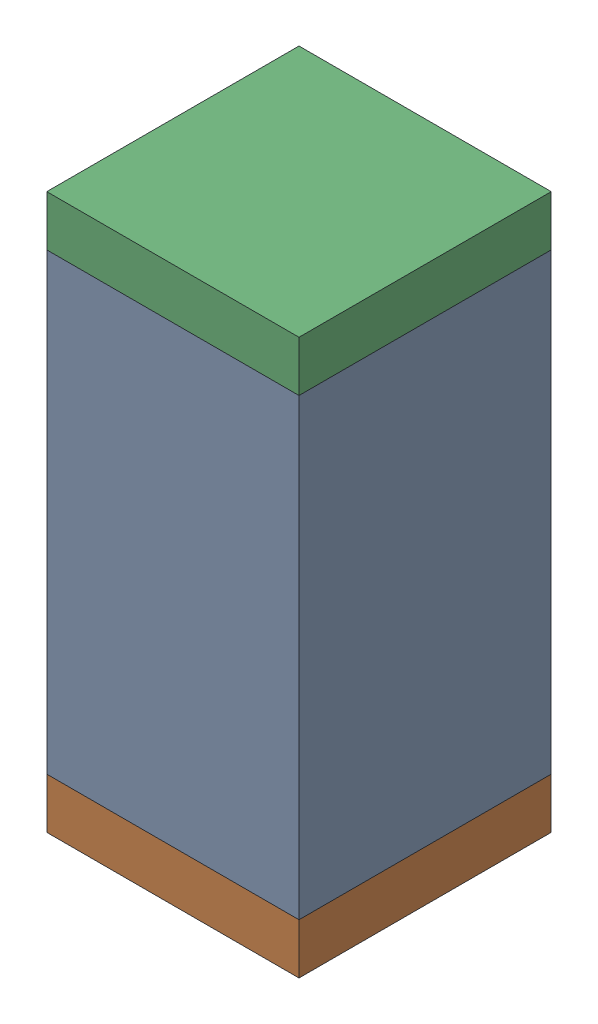
SolidWorks assembly C90, configuration Default. Lengths in mm.
Overall size (0.5 1.1 0.5).
6 component instances, 2 part files, 0 mates.
Components (placement in the parent):
- 791586336-1: 791586336 [Default] at (110.3 65.85 0) size (0.5 0.9 0.5)
  - Extruded_8-1: Extruded_8 [Default] at origin size (0.5 0.9 0.5)
- 810157360-1: 810157360 [Default] at (110.3 65.35 0) size (0.5 0.1 0.5)
  - Extruded_9-1: Extruded_9 [Default] at origin size (0.5 0.1 0.5)
- 810157360-2: 810157360 [Default] at (110.3 66.35 0) size (0.5 0.1 0.5)
  - Extruded_9-1: Extruded_9 [Default] at origin size (0.5 0.1 0.5)
